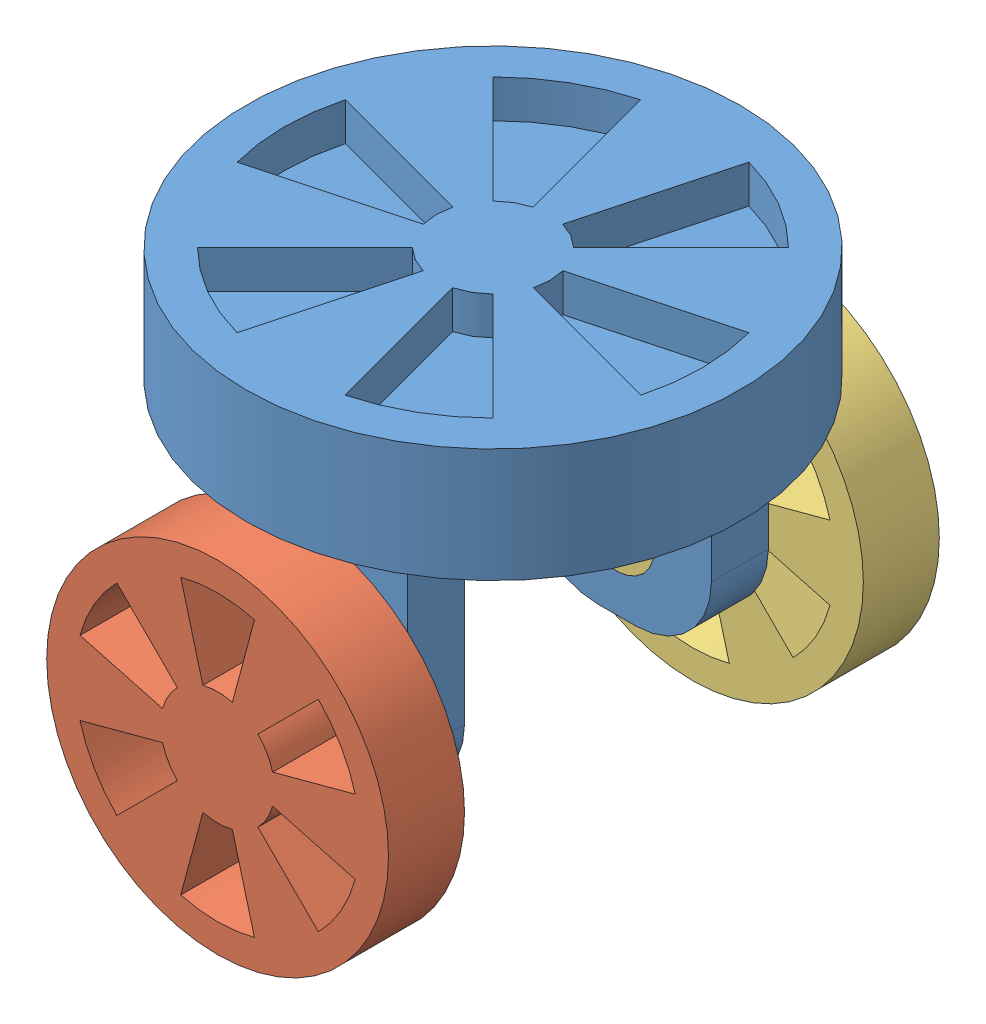
SolidWorks assembly 装配体9, configuration 默认. Lengths in mm.
Overall size (130 125 145).
3 component instances, 3 part files, 4 mates.
Components (placement in the parent):
- turntable_3-1: turntable_3 [默认] at (5.8076 17.6674 130) size (130 100 130)
- wheel_3_1-1: wheel_3_1 [默认] at (5.8076 -32.3326 162.5) x (0 0 1) z (-1 0 0) size (40 90 90)
- wheel_3_2-1: wheel_3_2 [默认] at (5.8076 -32.3326 97.5) x (0 0 -1) z (1 0 0) size (40 90 90)
Mates (geometry in assembly coordinates):
- 同心1: concentric: cylinder of turntable_3-1 through (5.8076 -32.3326 65) axis (0 0 1) radius 10; cylinder of ? through (5.8076 -32.3326 191.8078) axis (0 0 -1) radius 10
- 重合1: coincident: plane of assembly; plane of assembly; plane of turntable_3-1 through (-19.1924 -52.3326 162.5) normal (0 0 -1); plane of wheel_3_1-1 through (5.8076 -32.3326 162.5) normal (0 0 -1)
- 同心2: concentric: cylinder of turntable_3-1 through (5.8076 -32.3326 65) axis (0 0 1) radius 10; cylinder of ? through (5.8076 -32.3326 74.1308) axis (0 0 1) radius 10
- 重合2: coincident: plane of assembly; plane of assembly; plane of turntable_3-1 through (-19.1924 -52.3326 97.5) normal (0 0 1); plane of wheel_3_2-1 through (5.8076 -32.3326 97.5) normal (0 0 1)
